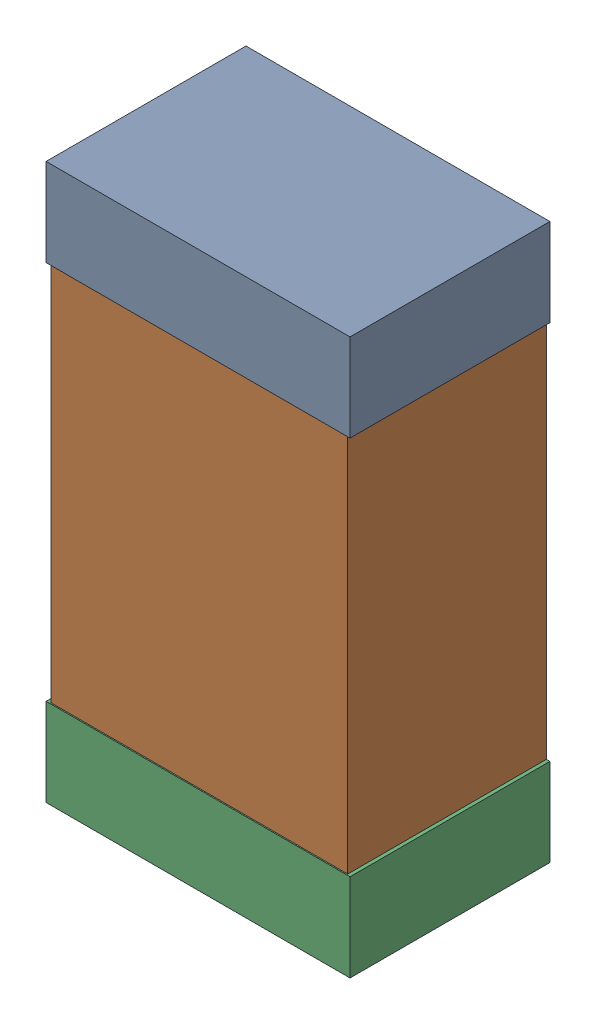
SolidWorks assembly Kanaloa_v2.0.0_Power_4, configuration Default. Lengths in mm.
Overall size (1.3 2.38 0.85).
6 component instances, 2 part files, 0 mates.
Components (placement in the parent):
- 330415056-1: 330415056 [Default] at (61.875 139.175 0) size (1.3 0.38 0.85)
  - Extruded_2-1: Extruded_2 [Default] at origin size (1.3 0.38 0.85)
- 352877008-1: 352877008 [Default] at (61.875 138.175 0) size (1.27 2.2 0.85)
  - Extruded_3-1: Extruded_3 [Default] at origin size (1.27 2.2 0.85)
- 330415056-2: 330415056 [Default] at (61.875 137.175 0) size (1.3 0.38 0.85)
  - Extruded_2-1: Extruded_2 [Default] at origin size (1.3 0.38 0.85)
